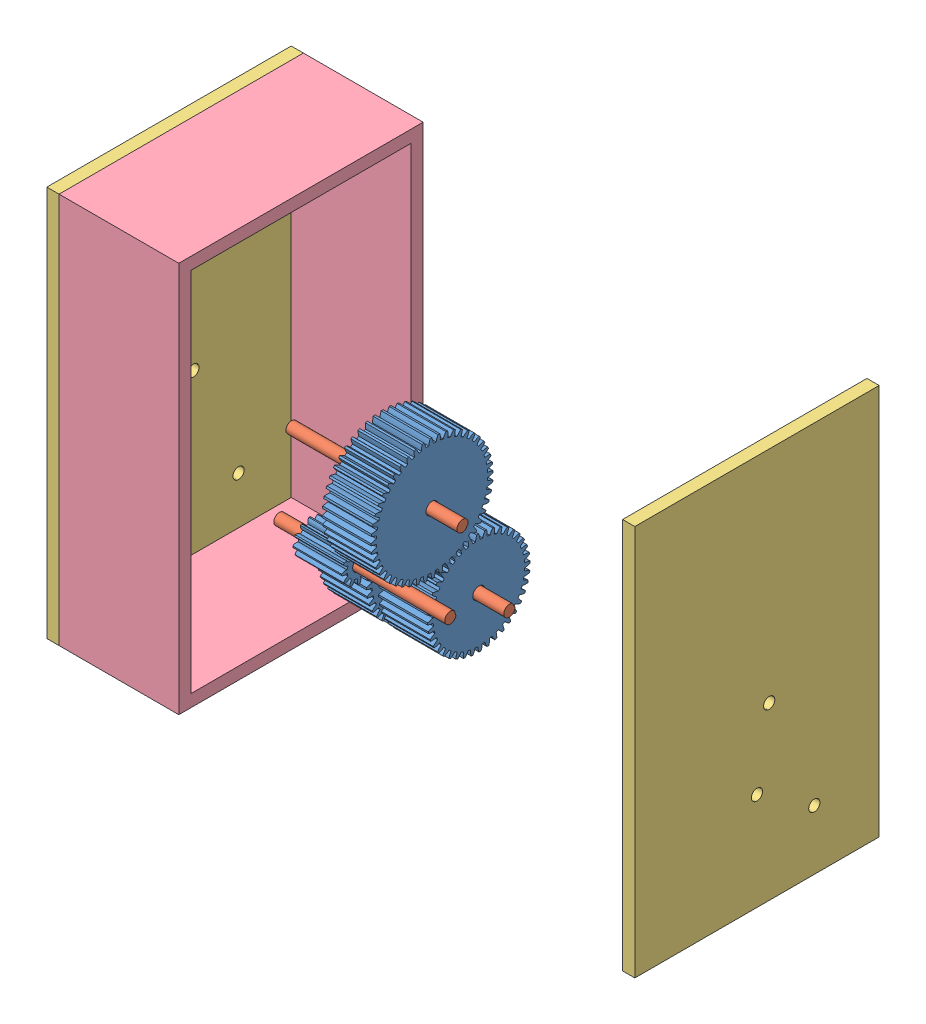
SolidWorks assembly Gearbox 2 attempt, configuration Default. Lengths in mm.
Overall size (305.58 203.2 165.1).
10 component instances, 4 part files, 28 mates.
Components (placement in the parent):
- spur gear_ai-1: spur gear_ai [Inch - Spur gear 20DP 48T 14.5PA 1/2FW ---S48N3.0H2.0L0.25N] at (6.35 -13.5247 16.7061) x (1 0 0) z (0 0.841458 -0.540322) size (25.4 63.42 63.42)
- spur gear_ai-4: spur gear_ai [Inch - Spur gear 20DP 40T 14.5PA 1/2FW ---S40N3.0H2.0L0.25N] at (-25.4 -63.8292 -7.6257) x (1 0 0) z (0 0.542598 -0.839992) size (25.4 53.24 53.24)
- spur gear_ai-5: spur gear_ai [Inch - Spur gear 20DP 40T 14.5PA 1/2FW ---S40N3.0H2.0L0.25N] at (6.35 -63.8292 -7.6257) x (1 0 0) z (0 0.839992 0.542598) size (25.4 53.24 53.24)
- spur gear_ai-3: spur gear_ai [Inch - Spur gear 20DP 12T 14.5PA 1FW ---S12N3.0H2.0L0.25N] at (-25.4 -51.6247 23.0561) x (1 0 0) z (0 0.960374 0.278714) size (25.4 17.34 17.34)
- Gearbox 3.5inch shaft (.23D)-1: Gearbox 3.5inch shaft (.23D) [Default] at (47.625 -13.5247 16.7061) x (0 -0.540322 -0.841458) z (-1 0 0) size (5.51 5.84 88.9)
- Gearbox 3.5inch shaft (.23D)-2: Gearbox 3.5inch shaft (.23D) [Default] at (47.625 -63.8292 -7.6257) x (0 0.542598 -0.839992) z (-1 0 0) size (5.51 5.84 88.9)
- Gearbox 3.5inch shaft (.23D)-3: Gearbox 3.5inch shaft (.23D) [Default] at (47.625 -51.6247 23.0561) x (0 0.278714 -0.960374) z (-1 0 0) size (5.51 5.84 88.9)
- Gearbox Side Panels-1: Gearbox Side Panels [Default] at (-98.6138 61.8947 22.4455) x (0 0 -1) z (1 0 0) size (127 203.2 6.35)
- Gearbox Side Panels-2: Gearbox Side Panels [Default] at (200.6158 61.8947 22.4455) x (0 0 -1) z (1 0 0) size (127 203.2 6.35)
- Gearbox Body-1: Gearbox Body [Default] at (-92.2638 -102.4247 86.5561) x (0 0 -1) z (1 0 0) size (127 203.2 62.23)
Mates (geometry in assembly coordinates):
- Coincident2: coincident: plane of spur gear_ai-3 through (0 -51.6247 23.0561) normal (1 0 0); circle of assembly
- Concentric7: concentric: cylinder of spur gear_ai-1 through (57.1501 -13.5247 16.7061) axis (-1 0 0) radius 3.175; circle of assembly
- Concentric8: concentric: cylinder of spur gear_ai-3 through (25.4001 -51.6247 23.0561) axis (-1 0 0) radius 3.175; circle of assembly
- Concentric9: concentric: cylinder of spur gear_ai-4 through (25.4001 -63.8292 -7.6257) axis (-1 0 0) radius 3.175; circle of assembly
- Coincident10: coincident: plane of spur gear_ai-4 through (0 -63.8292 -7.6257) normal (1 0 0); circle of assembly
- Concentric10: concentric: cylinder of spur gear_ai-3 through (25.4001 -51.6247 23.0561) axis (-1 0 0) radius 3.175; cylinder of Gearbox 3.5inch shaft (.23D)-3 through (-41.275 -51.6247 23.0561) axis (1 0 0) radius 2.921
- Coincident12: coincident: plane of spur gear_ai-3 through (-25.4 -51.6247 23.0561) normal (0 0.960374 0.278714); plane of Gearbox 3.5inch shaft (.23D)-3 through (47.625 -51.6247 23.0561) normal (0 -0.960374 -0.278714)
- Concentric11: concentric: cylinder of spur gear_ai-4 through (25.4001 -63.8292 -7.6257) axis (-1 0 0) radius 3.175; cylinder of Gearbox 3.5inch shaft (.23D)-2 through (-41.275 -63.8292 -7.6257) axis (1 0 0) radius 2.921
- Concentric12: concentric: cylinder of spur gear_ai-1 through (57.1501 -13.5247 16.7061) axis (-1 0 0) radius 3.175; cylinder of Gearbox 3.5inch shaft (.23D)-1 through (-41.275 -13.5247 16.7061) axis (1 0 0) radius 2.921
- Coincident17: coincident: plane of spur gear_ai-1 through (6.35 -13.5247 16.7061) normal (0 0.841458 -0.540322); plane of Gearbox 3.5inch shaft (.23D)-1 through (47.625 -13.5247 16.7061) normal (0 -0.841458 0.540322)
- Coincident18: coincident: plane of spur gear_ai-4 through (-25.4 -63.8292 -7.6257) normal (0 -0.839992 -0.542598); plane of Gearbox 3.5inch shaft (.23D)-2 through (47.625 -63.8292 -7.6257) normal (0 -0.839992 -0.542598)
- Concentric13: concentric: cylinder of spur gear_ai-5 through (57.1501 -63.8292 -7.6257) axis (-1 0 0) radius 3.175; cylinder of Gearbox 3.5inch shaft (.23D)-2 through (-41.275 -63.8292 -7.6257) axis (1 0 0) radius 2.921
- Distance6: distance = 6.35 mm: plane of spur gear_ai-5 through (6.35 -63.8292 -7.6257) normal (-1 0 0); plane of spur gear_ai-4 through (0 -63.8292 -7.6257) normal (1 0 0)
- Distance8: distance = 15.875 mm: plane of Gearbox 3.5inch shaft (.23D)-2 through (-41.275 -63.8292 -7.6257) normal (-1 0 0); plane of spur gear_ai-4 through (-25.4 -63.8292 -7.6257) normal (-1 0 0)
- Distance9: distance = 15.875 mm: plane of Gearbox 3.5inch shaft (.23D)-3 through (-41.275 -51.6247 23.0561) normal (-1 0 0); plane of spur gear_ai-3 through (-25.4 -51.6247 23.0561) normal (-1 0 0)
- Coincident24: coincident: plane of spur gear_ai-4 through (-25.4 -63.8292 -7.6257) normal (-1 0 0); plane of spur gear_ai-3 through (-25.4 -51.6247 23.0561) normal (-1 0 0)
- Coincident25: coincident: plane of Gearbox 3.5inch shaft (.23D)-1 through (-41.275 -13.5247 16.7061) normal (-1 0 0); plane of Gearbox 3.5inch shaft (.23D)-3 through (-41.275 -51.6247 23.0561) normal (-1 0 0)
- Distance10: distance = 47.625 mm: plane of Gearbox 3.5inch shaft (.23D)-1 through (-41.275 -13.5247 16.7061) normal (-1 0 0); plane of spur gear_ai-1 through (6.35 -13.5247 16.7061) normal (-1 0 0)
- Coincident27: coincident: plane of spur gear_ai-5 through (6.35 -63.8292 -7.6257) normal (0 0.839992 0.542598); plane of Gearbox 3.5inch shaft (.23D)-2 through (47.625 -63.8292 -7.6257) normal (0 -0.839992 -0.542598)
- Concentric14: concentric: cylinder of Gearbox 3.5inch shaft (.23D)-1 through (-41.275 -13.5247 16.7061) axis (1 0 0) radius 2.921; cylinder of Gearbox Side Panels-1 through (-92.2638 -13.5247 16.7061) axis (-1 0 0) radius 2.921
- Parallel1: parallel: cylinder of Gearbox 3.5inch shaft (.23D)-2 through (-41.275 -63.8292 -7.6257) axis (1 0 0) radius 2.921; cylinder of Gearbox Side Panels-1 through (-92.2638 -71.414 -6.7365) axis (-1 0 0) radius 2.921
- Concentric16: concentric: cylinder of Gearbox 3.5inch shaft (.23D)-3 through (-41.275 -51.6247 23.0561) axis (1 0 0) radius 2.921; cylinder of Gearbox Side Panels-1 through (-92.2638 -51.6247 23.0561) axis (-1 0 0) radius 2.921
- Concentric17: concentric: cylinder of Gearbox 3.5inch shaft (.23D)-1 through (-41.275 -13.5247 16.7061) axis (1 0 0) radius 2.921; cylinder of Gearbox Side Panels-2 through (206.9658 -13.5247 16.7061) axis (-1 0 0) radius 2.921
- Concentric18: concentric: cylinder of Gearbox 3.5inch shaft (.23D)-3 through (-41.275 -51.6247 23.0561) axis (1 0 0) radius 2.921; cylinder of Gearbox Side Panels-2 through (206.9658 -51.6247 23.0561) axis (-1 0 0) radius 2.921
- Parallel2: parallel: cylinder of Gearbox 3.5inch shaft (.23D)-2 through (-41.275 -63.8292 -7.6257) axis (1 0 0) radius 2.921; cylinder of Gearbox Side Panels-2 through (206.9658 -71.414 -6.7365) axis (-1 0 0) radius 2.921
- Coincident29: coincident: plane of Gearbox Side Panels-1 through (-92.2638 61.8947 22.4455) normal (1 0 0); plane of Gearbox Body-1 through (-92.2638 -102.4247 86.5561) normal (-1 0 0)
- Coincident30: coincident: plane of Gearbox Side Panels-1 through (-92.2638 100.7753 22.4455) normal (0 1 0); plane of Gearbox Body-1 through (-30.0338 100.7753 86.5561) normal (0 1 0)
- Coincident31: coincident: plane of Gearbox Side Panels-1 through (-92.2638 61.8947 -40.4439) normal (0 0 -1); plane of Gearbox Body-1 through (-30.0338 -102.4247 -40.4439) normal (0 0 -1)
